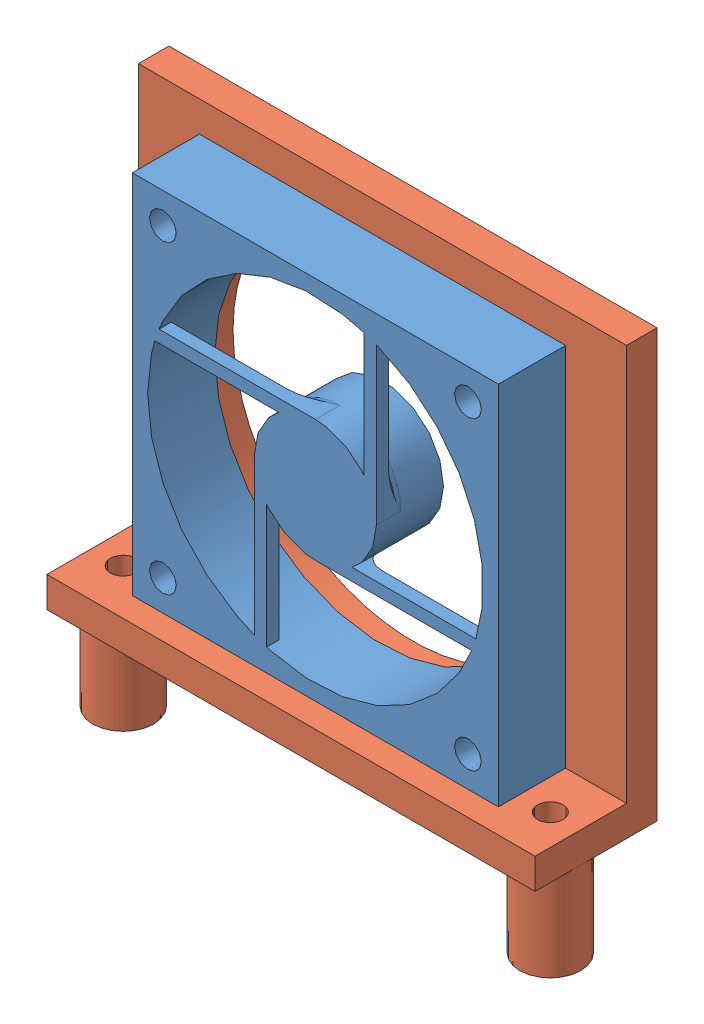
SolidWorks assembly Вентиллятор с креплением, configuration По умолчанию. Lengths in mm.
Overall size (80 85 20).
2 component instances, 2 part files, 3 mates.
Components (placement in the parent):
- Вентиллятор-1: Вентиллятор [По умолчанию] at origin size (60 60 11)
- Деталь1^Вентиллятор с креплением-1: Деталь1^Вентиллятор с креплением [По умолчанию] at origin size (80 85 20) (virtual)
Mates (geometry in assembly coordinates):
- Совпадение1: coincident aligned: plane of Вентиллятор-1 through (0 0 0) normal (0 0 1); plane of assembly through (0 0 0) normal (0 0 1)
- Совпадение2: coincident aligned: plane of Вентиллятор-1 through (0 0 0) normal (0 1 0); plane of assembly through (0 0 0) normal (0 1 0)
- Совпадение3: coincident aligned: plane of Вентиллятор-1 through (0 0 0) normal (1 0 0); plane of assembly through (0 0 0) normal (1 0 0)
